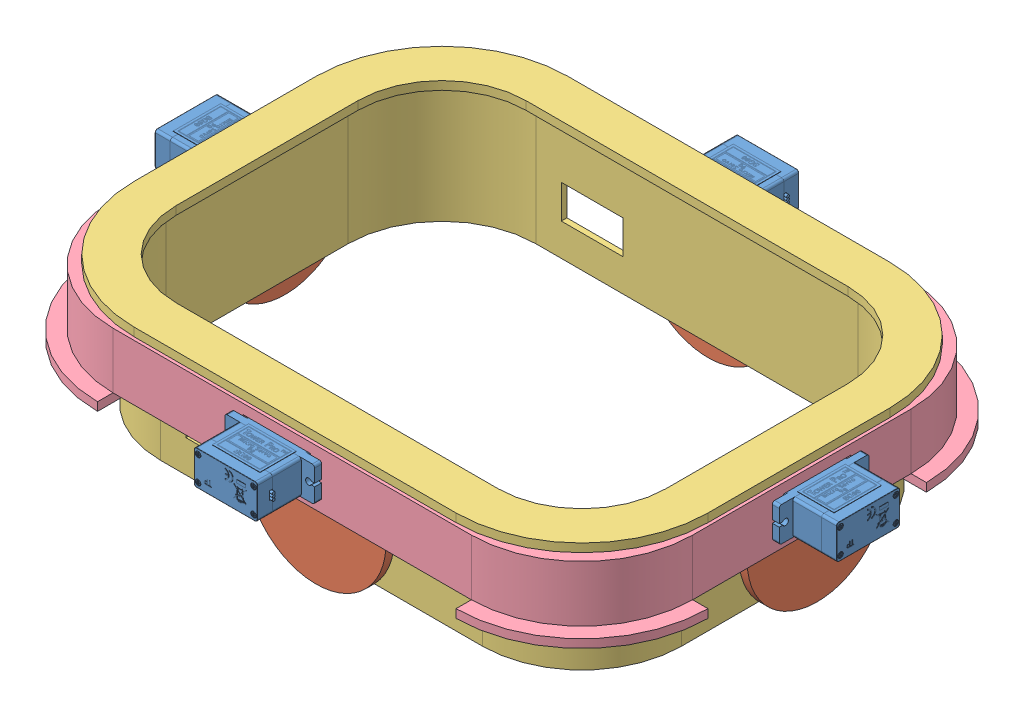
SolidWorks assembly CAM_Assembly_v2, configuration Default. Lengths in mm.
Overall size (243.6 55.89 193.6).
11 component instances, 4 part files, 16 mates.
Components (placement in the parent):
- SG90 - Micro Servo 9g - Tower Pro.1-1: SG90 - Micro Servo 9g - Tower Pro.1 [Peça] at (90.0304 145.6154 158.621) x (-1 0 0) z (0 1 0) size (32.1 29.95 12.4)
- SG90 - Micro Servo 9g - Tower Pro.1-2: SG90 - Micro Servo 9g - Tower Pro.1 [Peça] at (90.0304 145.6154 330.921) x (-1 0 0) z (0 -1 0) size (32.1 29.95 12.4)
- SG90 - Micro Servo 9g - Tower Pro.1-3: SG90 - Micro Servo 9g - Tower Pro.1 [Peça] at (206.6804 145.6154 239.271) x (0 0 1) z (0 -1 0) size (32.1 29.95 12.4)
- SG90 - Micro Servo 9g - Tower Pro.1-4: SG90 - Micro Servo 9g - Tower Pro.1 [Peça] at (-15.6196 145.6154 239.271) x (0 0 1) z (0 1 0) size (32.1 29.95 12.4)
- Assem1^CAM_Assembly_v2-1: Assem1^CAM_Assembly_v2 [Default] at origin size (218 55.89 168) (virtual)
  - CAM-1: CAM [V2] at (189.0304 145.6154 234.121) x (0 0.123113 -0.992393) z (1 0 0) size (50 50 6.8)
  - CAM-2: CAM [V2] at (95.1804 145.6154 176.271) x (-0.992393 -0.123113 0) z (0 0 -1) size (50 50 6.8)
  - CAM-3: CAM [V2] at (95.1804 145.6154 313.271) x (0.992393 0.123113 0) z (0 0 1) size (50 50 6.8)
  - CAM-4: CAM [V2] at (2.0304 145.6154 234.121) x (0 -0.123113 0.992393) z (-1 0 0) size (50 50 6.8)
  - Food_Holder-1: Food_Holder [Default] at (95.5304 155.7295 244.771) size (205 46 155)
  - Servo_Holder_v2-1: Servo_Holder_v2 [Default] at (95.5304 135.6154 244.771) size (218 23 168)
Mates (geometry in assembly coordinates):
- Concentric8: concentric aligned: circle of SG90 - Micro Servo 9g - Tower Pro.1-3; circle of Assem1^CAM_Assembly_v2-1/CAM-1
- Concentric9: concentric aligned: circle of SG90 - Micro Servo 9g - Tower Pro.1-1; circle of Assem1^CAM_Assembly_v2-1/CAM-2
- Concentric10: concentric aligned: circle of SG90 - Micro Servo 9g - Tower Pro.1-2; circle of Assem1^CAM_Assembly_v2-1/CAM-3
- Concentric11: concentric aligned: circle of SG90 - Micro Servo 9g - Tower Pro.1-4; circle of Assem1^CAM_Assembly_v2-1/CAM-4
- Width15: width aligned: plane of SG90 - Micro Servo 9g - Tower Pro.1-1 through (101.2804 140.3654 218.6657) normal (1 0 0); plane of Assem1^CAM_Assembly_v2-1/Servo_Holder_v2-1 through (78.7804 150.8654 218.6657) normal (-1 0 0); plane of SG90 - Micro Servo 9g - Tower Pro.1-1 through (78.0304 135.6154 138.9763) normal (1 0 0); plane of Assem1^CAM_Assembly_v2-1/Servo_Holder_v2-1 through (102.0304 135.6154 138.9763) normal (-1 0 0)
- Width16: width aligned: plane of SG90 - Micro Servo 9g - Tower Pro.1-1 through (105.2304 151.7154 166.271) normal (0 1 0); plane of Assem1^CAM_Assembly_v2-1/Servo_Holder_v2-1 through (105.2304 139.5154 166.271) normal (0 -1 0); plane of SG90 - Micro Servo 9g - Tower Pro.1-1 through (95.5304 139.1154 138.9763) normal (0 1 0); plane of Assem1^CAM_Assembly_v2-1/Servo_Holder_v2-1 through (95.5304 152.1154 138.9763) normal (0 -1 0)
- Coincident5: coincident anti-aligned: plane of Assem1^CAM_Assembly_v2-1/Servo_Holder_v2-1 through (95.5304 155.6154 166.271) normal (0 0 -1); plane of SG90 - Micro Servo 9g - Tower Pro.1-1 through (105.2304 150.8654 166.271) normal (0 0 1)
- Width17: width anti-aligned: plane of SG90 - Micro Servo 9g - Tower Pro.1-4 through (44.4251 150.8654 250.521) normal (0 0 1); plane of Assem1^CAM_Assembly_v2-1/Servo_Holder_v2-1 through (44.4251 140.3654 228.021) normal (0 0 -1); plane of SG90 - Micro Servo 9g - Tower Pro.1-4 through (226.3251 135.6154 251.271) normal (0 0 -1); plane of Assem1^CAM_Assembly_v2-1/Servo_Holder_v2-1 through (226.3251 135.6154 227.271) normal (0 0 1)
- Width18: width anti-aligned: plane of Assem1^CAM_Assembly_v2-1/Servo_Holder_v2-1 through (226.3251 139.1154 244.771) normal (0 1 0); plane of SG90 - Micro Servo 9g - Tower Pro.1-4 through (226.3251 152.1154 244.771) normal (0 -1 0); plane of Assem1^CAM_Assembly_v2-1/Servo_Holder_v2-1 through (-7.9696 139.5154 224.071) normal (0 -1 0); plane of SG90 - Micro Servo 9g - Tower Pro.1-4 through (-7.9696 151.7154 224.071) normal (0 1 0)
- Coincident6: coincident anti-aligned: plane of Assem1^CAM_Assembly_v2-1/Servo_Holder_v2-1 through (-7.9696 155.6154 244.771) normal (-1 0 0); plane of SG90 - Micro Servo 9g - Tower Pro.1-4 through (-7.9696 150.8654 224.071) normal (1 0 0)
- Width19: width anti-aligned: plane of SG90 - Micro Servo 9g - Tower Pro.1-3 through (146.6356 150.8654 228.021) normal (0 0 -1); plane of Assem1^CAM_Assembly_v2-1/Servo_Holder_v2-1 through (146.6356 140.3654 250.521) normal (0 0 1); plane of SG90 - Micro Servo 9g - Tower Pro.1-3 through (226.3251 135.6154 227.271) normal (0 0 1); plane of Assem1^CAM_Assembly_v2-1/Servo_Holder_v2-1 through (226.3251 135.6154 251.271) normal (0 0 -1)
- Width20: width aligned: plane of Assem1^CAM_Assembly_v2-1/Servo_Holder_v2-1 through (226.3251 139.1154 244.771) normal (0 1 0); plane of SG90 - Micro Servo 9g - Tower Pro.1-3 through (226.3251 152.1154 244.771) normal (0 -1 0); plane of Assem1^CAM_Assembly_v2-1/Servo_Holder_v2-1 through (199.0304 151.7154 224.071) normal (0 1 0); plane of SG90 - Micro Servo 9g - Tower Pro.1-3 through (199.0304 139.5154 224.071) normal (0 -1 0)
- Width21: width anti-aligned: plane of SG90 - Micro Servo 9g - Tower Pro.1-2 through (101.2804 150.8654 270.8763) normal (1 0 0); plane of Assem1^CAM_Assembly_v2-1/Servo_Holder_v2-1 through (78.7804 140.3654 270.8763) normal (-1 0 0); plane of SG90 - Micro Servo 9g - Tower Pro.1-2 through (102.0304 135.6154 138.9763) normal (-1 0 0); plane of Assem1^CAM_Assembly_v2-1/Servo_Holder_v2-1 through (78.0304 135.6154 138.9763) normal (1 0 0)
- Width22: width anti-aligned: plane of SG90 - Micro Servo 9g - Tower Pro.1-2 through (105.2304 151.7154 323.271) normal (0 1 0); plane of Assem1^CAM_Assembly_v2-1/Servo_Holder_v2-1 through (105.2304 139.5154 323.271) normal (0 -1 0); plane of SG90 - Micro Servo 9g - Tower Pro.1-2 through (95.5304 152.1154 138.9763) normal (0 -1 0); plane of Assem1^CAM_Assembly_v2-1/Servo_Holder_v2-1 through (95.5304 139.1154 138.9763) normal (0 1 0)
- Coincident7: coincident anti-aligned: plane of Assem1^CAM_Assembly_v2-1/Servo_Holder_v2-1 through (95.5304 155.6154 323.271) normal (0 0 1); plane of SG90 - Micro Servo 9g - Tower Pro.1-2 through (105.2304 140.3654 323.271) normal (0 0 -1)
- Coincident8: coincident anti-aligned: plane of Assem1^CAM_Assembly_v2-1/Servo_Holder_v2-1 through (199.0304 155.6154 244.771) normal (1 0 0); plane of SG90 - Micro Servo 9g - Tower Pro.1-3 through (199.0304 140.3654 224.071) normal (-1 0 0)
